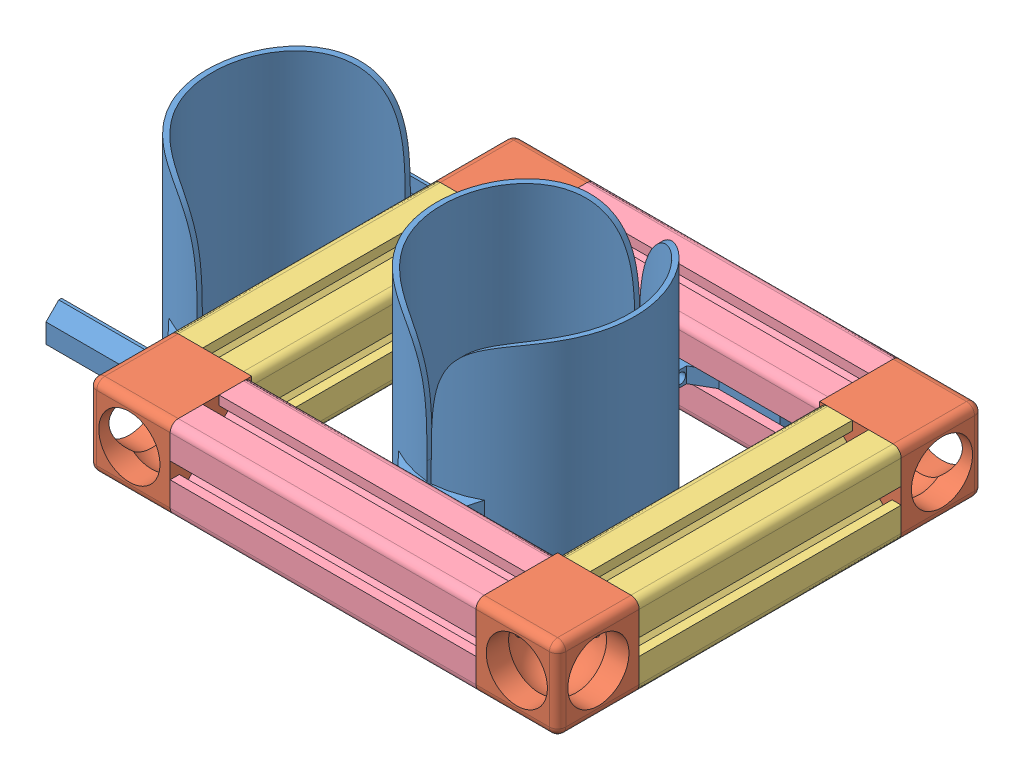
SolidWorks assembly inner_ring, configuration Standard. Lengths in mm.
Overall size (230 156.99 208.5).
11 component instances, 4 part files, 29 mates.
Components (placement in the parent):
- clamp-2: clamp [Standard] at (-470.0282 -68.2258 71.3696) size (53.5 156.99 152.82)
- 2D_corner-1: 2D_corner [Standard] at (-561.0771 -68.2258 155.6196) x (-1 0 0) z (0 1 0) size (40 40 40)
- 2D_corner-2: 2D_corner [Standard] at (-371.0771 -68.2258 -12.8804) x (0 0 -1) z (0 -1 0) size (40 40 40)
- 2D_corner-3: 2D_corner [Standard] at (-371.0771 -68.2258 155.6196) x (1 0 0) z (0 -1 0) size (40 40 40)
- 2D_corner-4: 2D_corner [Standard] at (-561.0771 -68.2258 -12.8804) x (0 0 -1) z (0 1 0) size (40 40 40)
- aluminum_40x40x128.5_profile-5: aluminum_40x40x128.5_profile [Standard] at (-363.1445 -57.366 71.3696) x (1 0 0) z (0 -1 0) size (40 128.5 40)
- aluminum_40x40x128.5_profile-6: aluminum_40x40x128.5_profile [Standard] at (-553.1445 -57.366 71.3696) x (1 0 0) z (0 -1 0) size (40 128.5 40)
- aluminum_40x40x150_profile-1: aluminum_40x40x150_profile [Standard] at (-466.0771 -57.366 147.687) x (0 0 -1) z (0 -1 0) size (40 150 40)
- aluminum_40x40x150_profile-2: aluminum_40x40x150_profile [Standard] at (-466.0771 -57.366 -20.813) x (0 0 -1) z (0 -1 0) size (40 150 40)
- clamp-3: clamp [Standard] at (-574.7896 -68.2258 71.3696) x (-1 0 0) z (0 0 -1) size (53.5 156.99 152.82)
- clamp-4: clamp [Standard] at (-462.126 -68.2258 71.3696) x (-1 0 0) z (0 0 -1) size (53.5 156.99 152.82)
Mates (geometry in assembly coordinates):
- Coincident22: coincident anti-aligned: plane of 2D_corner-4 through (-581.0771 -48.2258 7.1196) normal (0 0 1); plane of aluminum_40x40x128.5_profile-6 through (-553.1445 -57.366 7.1196) normal (0 0 -1)
- Coincident23: coincident aligned: plane of 2D_corner-4 through (-541.0771 -68.2258 -12.8804) normal (1 0 0); plane of aluminum_40x40x128.5_profile-6 through (-541.0771 -57.366 135.6196) normal (1 0 0)
- Coincident24: coincident aligned: plane of 2D_corner-4 through (-581.0771 -48.2258 -32.8804) normal (0 1 0); plane of aluminum_40x40x128.5_profile-6 through (-553.1445 -48.2258 135.6196) normal (0 1 0)
- Coincident25: coincident anti-aligned: plane of 2D_corner-1 through (-561.0771 -68.2258 135.6196) normal (0 0 -1); plane of aluminum_40x40x128.5_profile-6 through (-553.1445 -57.366 135.6196) normal (0 0 1)
- Coincident26: coincident aligned: plane of 2D_corner-1 through (-541.0771 -48.2258 175.6196) normal (1 0 0); plane of aluminum_40x40x128.5_profile-6 through (-541.0771 -57.366 135.6196) normal (1 0 0)
- Coincident27: coincident aligned: plane of 2D_corner-1 through (-581.0771 -88.2258 175.6196) normal (0 -1 0); plane of aluminum_40x40x128.5_profile-6 through (-553.1445 -88.2258 135.6196) normal (0 -1 0)
- Coincident28: coincident anti-aligned: plane of 2D_corner-2 through (-351.0771 -88.2258 7.1196) normal (0 0 1); plane of aluminum_40x40x128.5_profile-5 through (-363.1445 -57.366 7.1196) normal (0 0 -1)
- Coincident29: coincident aligned: plane of 2D_corner-2 through (-351.0771 -68.2258 -12.8804) normal (1 0 0); plane of aluminum_40x40x128.5_profile-5 through (-351.0771 -57.366 135.6196) normal (1 0 0)
- Coincident30: coincident aligned: plane of 2D_corner-2 through (-351.0771 -88.2258 -32.8804) normal (0 -1 0); plane of aluminum_40x40x128.5_profile-5 through (-363.1445 -88.2258 135.6196) normal (0 -1 0)
- Coincident31: coincident anti-aligned: plane of 2D_corner-3 through (-371.0771 -68.2258 135.6196) normal (0 0 -1); plane of aluminum_40x40x128.5_profile-5 through (-363.1445 -57.366 135.6196) normal (0 0 1)
- Coincident32: coincident aligned: plane of 2D_corner-3 through (-351.0771 -88.2258 175.6196) normal (1 0 0); plane of aluminum_40x40x128.5_profile-5 through (-351.0771 -57.366 135.6196) normal (1 0 0)
- Coincident33: coincident aligned: plane of 2D_corner-3 through (-351.0771 -88.2258 175.6196) normal (0 -1 0); plane of aluminum_40x40x128.5_profile-5 through (-363.1445 -88.2258 135.6196) normal (0 -1 0)
- Coincident34: coincident anti-aligned: plane of 2D_corner-4 through (-541.0771 -68.2258 -12.8804) normal (1 0 0); plane of aluminum_40x40x200_profile-2 through (-541.0771 -57.366 -20.813) normal (-1 0 0)
- Coincident35: coincident aligned: plane of 2D_corner-4 through (-581.0771 -48.2258 -32.8804) normal (0 0 -1); plane of aluminum_40x40x200_profile-2 through (-391.0771 -57.366 -32.8804) normal (0 0 -1)
- Coincident36: coincident aligned: plane of 2D_corner-4 through (-581.0771 -88.2258 -32.8804) normal (0 -1 0); plane of aluminum_40x40x200_profile-2 through (-391.0771 -88.2258 -20.813) normal (0 -1 0)
- Coincident37: coincident aligned: plane of 2D_corner-2 through (-351.0771 -88.2258 -32.8804) normal (0 -1 0); plane of aluminum_40x40x200_profile-2 through (-391.0771 -88.2258 -20.813) normal (0 -1 0)
- Coincident38: coincident aligned: plane of 2D_corner-2 through (-351.0771 -88.2258 -32.8804) normal (0 0 -1); plane of aluminum_40x40x200_profile-2 through (-391.0771 -57.366 -32.8804) normal (0 0 -1)
- Coincident39: coincident anti-aligned: plane of 2D_corner-2 through (-391.0771 -68.2258 -12.8804) normal (-1 0 0); plane of aluminum_40x40x200_profile-2 through (-391.0771 -57.366 -20.813) normal (1 0 0)
- Coincident40: coincident anti-aligned: plane of 2D_corner-1 through (-541.0771 -48.2258 175.6196) normal (1 0 0); plane of aluminum_40x40x200_profile-1 through (-541.0771 -57.366 147.687) normal (-1 0 0)
- Coincident41: coincident aligned: plane of 2D_corner-1 through (-581.0771 -88.2258 175.6196) normal (0 -1 0); plane of aluminum_40x40x200_profile-1 through (-391.0771 -88.2258 147.687) normal (0 -1 0)
- Coincident42: coincident aligned: plane of 2D_corner-1 through (-561.0771 -68.2258 175.6196) normal (0 0 1); plane of aluminum_40x40x200_profile-1 through (-391.0771 -57.366 175.6196) normal (0 0 1)
- Width1: width anti-aligned: plane of clamp-2 through (-415.0282 -72.9758 147.7809) normal (0 0 1); plane of clamp-2 through (-415.0282 -72.9758 -5.0418) normal (0 0 -1); plane of aluminum_40x40x200_profile-1 through (-391.0771 -57.366 147.8696) normal (0 0 -1); plane of aluminum_40x40x200_profile-2 through (-391.0771 -57.366 -5.1304) normal (0 0 1)
- Width2: width anti-aligned: plane of clamp-2 through (-455.0282 -72.0258 71.3696) normal (0 -1 0); plane of clamp-2 through (-455.0282 -64.4258 71.3696) normal (0 1 0); plane of aluminum_40x40x200_profile-1 through (-391.0771 -72.2258 147.687) normal (0 1 0); plane of aluminum_40x40x200_profile-1 through (-391.0771 -64.2258 147.687) normal (0 -1 0)
- LimitDistance2: limit distance = 23.9511 mm anti-aligned: plane of clamp-2 through (-415.0282 -68.2258 71.3696) normal (1 0 0); plane of 2D_corner-2 through (-391.0771 -68.2258 -12.8804) normal (-1 0 0)
- LimitDistance4: limit distance = 88.7125 mm anti-aligned: plane of clamp-3 through (-579.7896 6.7742 130.7507) normal (1 0 0); plane of clamp-2 through (-465.0282 6.7742 11.9884) normal (-1 0 0)
- Concentric1: concentric anti-aligned: cylinder of clamp-2 through (-465.0292 -68.2258 11.3817) axis (1 0 0) radius 2.5; cylinder of clamp-4 through (-467.125 -68.2258 11.3817) axis (-1 0 0) radius 2.5
- Concentric2: concentric anti-aligned: cylinder of clamp-2 through (-465.0292 -68.2258 131.3574) axis (1 0 0) radius 2.5; cylinder of clamp-4 through (-467.125 -68.2258 131.3574) axis (-1 0 0) radius 2.5
- Symmetric1: symmetric aligned: cylinder of clamp-2 through (-470.0282 6.7742 71.3696) axis (0 -1 0) radius 52.5; cylinder of clamp-4 through (-462.126 6.7742 71.3696) axis (0 -1 0) radius 52.5
- LimitDistance5: limit distance = 23.9511 mm anti-aligned: plane of clamp-2 through (-415.0282 -68.2258 71.3696) normal (1 0 0); plane of 2D_corner-2 through (-391.0771 -68.2258 -12.8804) normal (-1 0 0)
